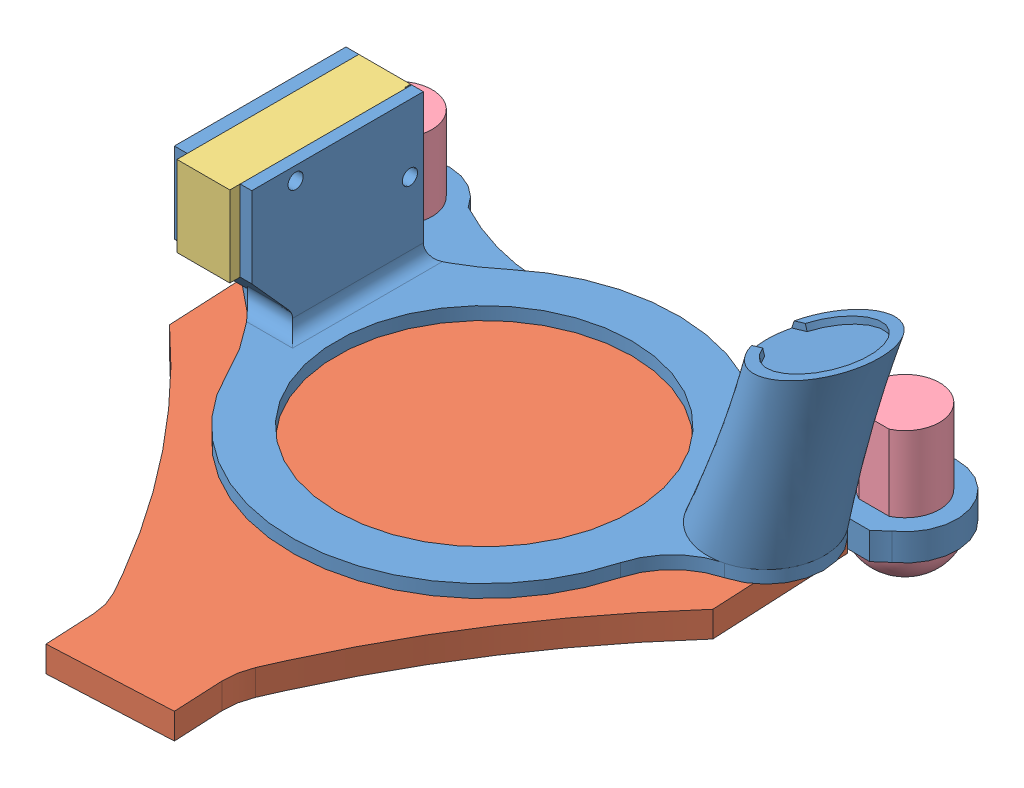
SolidWorks assembly wheel assembly, configuration Default. Lengths in mm.
Overall size (126.59 53.83 122.69).
5 component instances, 4 part files, 10 mates.
Components (placement in the parent):
- Paddle Enclosure-1: Paddle Enclosure [Default] at (-6.7326 -8.2104 -9.4051) size (126.59 53.15 81.03)
- steering_wheel-1: steering_wheel [Default] at (-6.6822 -13.2904 -3.2948) x (0.998814 0 -0.048696) z (0.048696 0 0.998814) size (102.11 5.08 111.76)
- Switch-1: Switch [Default] at (-54.1469 6.7756 2.1647) x (0 0 -1) z (0 -1 0) size (35.81 10.41 15.88)
- button-1: button [Default] at (-56.6869 -13.2904 -42.2981) x (-1 0 0) z (0 0 1) size (17.5 27.2 17.5)
- button-2: button [Default] at (43.2216 -13.2904 -42.2981) x (-1 0 0) z (0 0 1) size (17.5 27.2 17.5)
Mates (geometry in assembly coordinates):
- Coincident7: coincident anti-aligned: plane of Paddle Enclosure-1 through (-56.6869 6.7756 -9.4051) normal (0 1 0); plane of Switch-1 through (-43.7329 6.7756 3.6759) normal (0 -1 0)
- Coincident8: coincident anti-aligned: plane of Paddle Enclosure-1 through (-54.1469 22.6506 1.6439) normal (1 0 0); plane of Switch-1 through (-54.1469 6.7756 2.1647) normal (-1 0 0)
- Coincident9: coincident anti-aligned: plane of Paddle Enclosure-1 through (-6.7326 -8.2104 -9.4051) normal (0 -1 0); plane of steering_wheel-1 through (-6.6822 -8.2104 -3.2948) normal (0 1 0)
- Coincident12: coincident aligned: plane of Paddle Enclosure-1 through (-56.6869 -8.2104 -32.1381) normal (0 0 -1); plane of Switch-1 through (-43.7329 6.7756 -32.1381) normal (0 0 -1)
- Parallel1: parallel aligned: face of Paddle Enclosure-1; cylinder of steering_wheel-1 through (-6.6822 -8.2104 -3.2948) axis (0 -1 0) radius 40.64
- Coincident14: coincident: plane of Paddle Enclosure-1 through (-6.7326 -7.9564 -36.1894) normal (0 0 -1); plane of button-1 through (-59.6616 6.9026 -36.1894) normal (0 0 1)
- Concentric2: concentric: circle of Paddle Enclosure-1; circle of button-1
- Coincident15: coincident anti-aligned: plane of Paddle Enclosure-1 through (-6.7326 -13.2904 -9.4051) normal (0 -1 0); plane of button-1 through (-56.6869 -13.2904 -42.2981) normal (0 1 0)
- Coincident16: coincident: plane of Paddle Enclosure-1 through (-6.7326 -7.9564 -36.1894) normal (0 0 -1); plane of button-2 through (46.1365 -36.2571 -36.1894) normal (0 0 1)
- Coincident17: coincident anti-aligned: circle of Paddle Enclosure-1; circle of button-2
